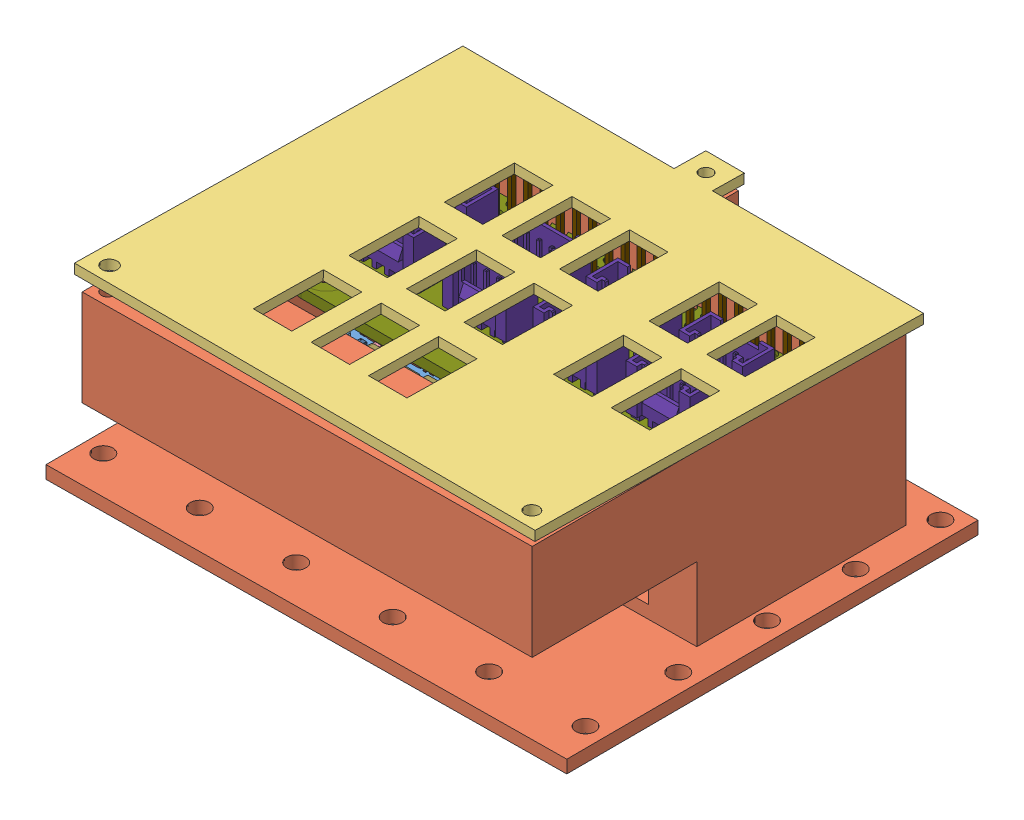
SolidWorks assembly RapberryPiZeroAndHat, configuration Default. Lengths in mm.
Overall size (81.55 32.34 66.18).
89 component instances, 21 part files, 142 mates.
Components (placement in the parent):
- Raspberry_pizero_PCB-1: Raspberry_pizero_PCB [Default] at (-51.2564 20.0966 13.0542) size (65 1 30)
- Micro USB_input_female (short)-SMT-1: Micro USB_input_female (short)-SMT [Default] at (-42.3564 22.3216 26.5042) size (7.98 2.94 5.43)
- Micro USB_input_female (short)-SMT-2: Micro USB_input_female (short)-SMT [Default] at (-29.7564 22.3216 26.5042) size (7.98 2.94 5.43)
- 0204 - Capacitor-1: 0204 - Capacitor [Default] at (-66.1059 21.3466 14.3973) size (1 0.5 0.6)
- 0204 - Capacitor-2: 0204 - Capacitor [Default] at (-66.1059 21.3466 13.6661) size (1 0.5 0.6)
- 0204 - Capacitor-3: 0204 - Capacitor [Default] at (-66.4957 21.3466 8.5689) size (1 0.5 0.6)
- 0204 - Capacitor-4: 0204 - Capacitor [Default] at (-66.4957 21.3466 9.5922) size (1 0.5 0.6)
- 0204 - Capacitor-5: 0204 - Capacitor [Default] at (-66.4957 21.3466 10.5547) size (1 0.5 0.6)
- 0204 - Capacitor-6: 0204 - Capacitor [Default] at (-66.4957 21.3466 11.4563) size (1 0.5 0.6)
- 0204 - Capacitor-7: 0204 - Capacitor [Default] at (-66.4957 21.3466 12.4125) size (1 0.5 0.6)
- 0204 - Capacitor-8: 0204 - Capacitor [Default] at (-54.2619 21.3466 22.342) size (1 0.5 0.6)
- 0204 - Capacitor-9: 0204 - Capacitor [Default] at (-54.2619 21.3466 24.3333) size (1 0.5 0.6)
- 0204 - Capacitor-10: 0204 - Capacitor [Default] at (-63.0188 21.3466 22.4185) x (0 0 1) z (-1 0 0) size (1 0.5 0.6)
- 0204 - Capacitor-11: 0204 - Capacitor [Default] at (-62.8505 21.3466 22.4185) x (0 0 -1) z (1 0 0) size (1 0.5 0.6)
- 0204 - Capacitor-12: 0204 - Capacitor [Default] at (-61.9536 21.3466 22.4185) x (0 0 -1) z (1 0 0) size (1 0.5 0.6)
- 0204 - Capacitor-13: 0204 - Capacitor [Default] at (-60.535 21.3466 22.4217) x (0 0 1) z (-1 0 0) size (1 0.5 0.6)
- 0204 - Capacitor-14: 0204 - Capacitor [Default] at (-60.2749 21.3466 22.4217) x (0 0 -1) z (1 0 0) size (1 0.5 0.6)
- 0204 - Capacitor-15: 0204 - Capacitor [Default] at (-59.4762 21.3466 22.4217) x (0 0 -1) z (1 0 0) size (1 0.5 0.6)
- 0204 - Capacitor-16: 0204 - Capacitor [Default] at (-58.5578 21.3466 22.4217) x (0 0 -1) z (1 0 0) size (1 0.5 0.6)
- 0204 - Capacitor-17: 0204 - Capacitor [Default] at (-57.7282 21.3466 22.4217) x (0 0 -1) z (1 0 0) size (1 0.5 0.6)
- 0204 - Capacitor-18: 0204 - Capacitor [Default] at (-49.7633 21.3466 17.2973) size (1 0.5 0.6)
- 0204 - Capacitor-19: 0204 - Capacitor [Default] at (-49.7656 21.3466 20.4911) size (1 0.5 0.6)
- 0204 - Capacitor-20: 0204 - Capacitor [Default] at (-49.7656 21.3466 19.5641) size (1 0.5 0.6)
- 0204 - Capacitor-21: 0204 - Capacitor [Default] at (-49.7656 21.3466 18.764) size (1 0.5 0.6)
- 0204 - Capacitor-22: 0204 - Capacitor [Default] at (-49.7656 21.3466 18.0575) size (1 0.5 0.6)
- 0204 - Capacitor-23: 0204 - Capacitor [Default] at (-50.3207 21.3466 16.1412) size (1 0.5 0.6)
- 0204 - Capacitor-24: 0204 - Capacitor [Default] at (-50.3207 21.3466 15.1225) size (1 0.5 0.6)
- 0204 - Capacitor-25: 0204 - Capacitor [Default] at (-50.3207 21.3466 14.0903) size (1 0.5 0.6)
- 0204 - Capacitor-26: 0204 - Capacitor [Default] at (-50.3207 21.3466 13.2438) size (1 0.5 0.6)
- 0204 - Capacitor-27: 0204 - Capacitor [Default] at (-44.527 21.3466 13.1418) size (1 0.5 0.6)
- 0204 - Capacitor-28: 0204 - Capacitor [Default] at (-44.527 21.3466 12.278) size (1 0.5 0.6)
- 0204 - Capacitor-29: 0204 - Capacitor [Default] at (-53.3159 21.3466 7.4799) size (1 0.5 0.6)
- 0204 - Capacitor-30: 0204 - Capacitor [Default] at (-59.3985 21.3466 7.1313) x (0 0 -1) z (1 0 0) size (1 0.5 0.6)
- 0204 - Capacitor-31: 0204 - Capacitor [Default] at (-57.9118 21.3466 7.1313) x (0 0 1) z (-1 0 0) size (1 0.5 0.6)
- 0204 - Capacitor-32: 0204 - Capacitor [Default] at (-63.5406 21.3466 7.1313) x (0 0 1) z (-1 0 0) size (1 0.5 0.6)
- 0204- Resistor-15: 0204- Resistor [Default] at (-44.5223 21.4522 15.4193) x (-1 0 0) z (0 -1 0) size (0.99 0.51 0.36)
- 0204- Resistor-14: 0204- Resistor [Default] at (-44.5223 21.4522 14.3417) x (-1 0 0) z (0 -1 0) size (0.99 0.51 0.36)
- 0204- Resistor-13: 0204- Resistor [Default] at (-44.5223 21.4522 12.4047) x (-1 0 0) z (0 -1 0) size (0.99 0.51 0.36)
- 0204- Resistor-4: 0204- Resistor [Default] at (-42.6936 21.4522 18.4076) x (-1 0 0) z (0 -1 0) size (0.99 0.51 0.36)
- 0204- Resistor-5: 0204- Resistor [Default] at (-39.831 21.4522 18.1462) x (0 0 1) z (0 -1 0) size (0.99 0.51 0.36)
- 0204- Resistor-7: 0204- Resistor [Default] at (-66.5004 21.4522 19.8533) x (-1 0 0) z (0 -1 0) size (0.99 0.51 0.36)
- 0204- Resistor-9: 0204- Resistor [Default] at (-79.148 21.4522 17.7279) x (-1 0 0) z (0 -1 0) size (0.99 0.51 0.36)
- 0204- Resistor-10: 0204- Resistor [Default] at (-60.3595 21.4522 7.1266) x (0 0 -1) z (0 -1 0) size (0.99 0.51 0.36)
- 0204- Resistor-11: 0204- Resistor [Default] at (-42.6893 21.4522 11.6167) x (-1 0 0) z (0 -1 0) size (0.99 0.51 0.36)
- 0204- Resistor-12: 0204- Resistor [Default] at (-21.8613 21.4522 20.9026) x (-1 0 0) z (0 -1 0) size (0.99 0.51 0.36)
- CAP-0306-1: CAP-0306 [Default] at (-50.0081 21.4966 8.9291) size (1.6 0.8 0.9)
- CAP-0306-2: CAP-0306 [Default] at (-82.3562 21.4966 19.4035) x (0 0 1) z (-1 0 0) size (1.6 0.8 0.9)
- Raspberry_pizero_BCM2835 with VC4-2: Raspberry_pizero_BCM2835 with VC4 [Default] at (-57.9267 21.5466 14.7194) x (1 0 0) z (0 0 -1) size (12 0.65 12)
- Crystal 3.4x2.4mm-1: Crystal 3.4x2.4mm [Default] at (-66.1441 21.0966 17.5946) x (0 0 1) z (-1 0 0) size (3.2 1 2.4)
- 0204- Resistor-16: 0204- Resistor [Default] at (-68.5745 21.4522 5.9384) x (0 0 1) z (0 -1 0) size (0.99 0.51 0.36)
- 0204- Resistor-17: 0204- Resistor [Default] at (-70.0781 21.4522 5.9384) x (0 0 1) z (0 -1 0) size (0.99 0.51 0.36)
- 0805- Capacitor-1: 0805- Capacitor [Default] at (-56.2106 21.9966 5.1919) x (1 0 0) z (0 -1 0) size (2 1.25 0.9)
- 0805- Capacitor-2: 0805- Capacitor [Default] at (-56.2106 21.9966 7.3589) x (1 0 0) z (0 -1 0) size (2 1.25 0.9)
- 0805- Capacitor-3: 0805- Capacitor [Default] at (-36.3007 21.9966 25.1368) x (1 0 0) z (0 -1 0) size (2 1.25 0.9)
- 0805- Capacitor-4: 0805- Capacitor [Default] at (-32.5762 21.9966 16.3326) x (0 0 1) z (0 -1 0) size (2 1.25 0.9)
- 0805- Capacitor-5: 0805- Capacitor [Default] at (-30.7451 21.9966 16.3326) x (0 0 -1) z (0 -1 0) size (2 1.25 0.9)
- 0805- Capacitor-6: 0805- Capacitor [Default] at (-26.001 21.9966 15.5523) x (0 0 -1) z (0 -1 0) size (2 1.25 0.9)
- 0805- Capacitor-7: 0805- Capacitor [Default] at (-24.0466 21.9966 15.5523) x (0 0 -1) z (0 -1 0) size (2 1.25 0.9)
- 0204 - Capacitor-33: 0204 - Capacitor [Default] at (-56.3601 21.3466 22.4168) x (0 0 1) z (-1 0 0) size (1 0.5 0.6)
- 0204 - Capacitor Brown-35: 0204 - Capacitor Brown [Default] at (-64.6013 21.3466 26.5277) size (1 0.5 0.6)
- 0204 - Capacitor Brown-36: 0204 - Capacitor Brown [Default] at (-50.3207 21.3466 12.214) size (1 0.5 0.6)
- 0204 - Capacitor Brown-37: 0204 - Capacitor Brown [Default] at (-50.3207 21.3466 11.0963) size (1 0.5 0.6)
- 0204 - Capacitor Brown-38: 0204 - Capacitor Brown [Default] at (-50.3207 21.3466 10.1084) size (1 0.5 0.6)
- 0204 - Capacitor Brown-39: 0204 - Capacitor Brown [Default] at (-44.527 21.3466 11.1151) size (1 0.5 0.6)
- 0204 - Capacitor Brown-40: 0204 - Capacitor Brown [Default] at (-42.694 21.3466 12.1364) size (1 0.5 0.6)
- 0204 - Capacitor Brown-41: 0204 - Capacitor Brown [Default] at (-80.9029 21.3466 20.8434) size (1 0.5 0.6)
- 0204- Resistor-21: 0204- Resistor [Default] at (-79.0538 21.4522 20.9432) x (1 0 0) z (0 -1 0) size (0.99 0.51 0.36)
- 6-Pin SOT-1: 6-Pin SOT [Default] at (-80.2098 21.0966 19.4296) x (0 0 1) z (0 1 0) size (1.5 1.84 0.95)
- micro sd molex-1: micro sd molex [Default] at (-74.7768 21.6766 -33.0961) x (0 0 1) z (0 1 0) size (11.95 11.4 1.45)
- hdmi type C-1: hdmi type C [Default] at (-71.3564 22.9466 28.6542) size (12.9 4.05 7.7)
- Voltage Regulator 3x3mm 12-Pin-1: Voltage Regulator 3x3mm 12-Pin [Default] at (-26.5859 21.0966 14.3315) x (1 0 0) z (0 1 0) size (3 4.1 1.2)
- 1210 inductor-1: 1210 inductor [Default] at (-50.6117 20.9774 6.5916) x (0 0 1) z (0 1 0) size (3.26 2.86 0.75)
- 0204 - Capacitor-34: 0204 - Capacitor [Default] at (-53.3159 21.3466 6.4804) size (1 0.5 0.6)
- raspberry_pi_B+_(bar_180_2x20)-1: raspberry_pi_B+_(bar_180_2x20) [Default] at (-75.3864 23.5966 0.2742) x (0 0 -1) z (-1 0 0) size (5.08 11.6 50.8)
- Grove Base Hat Zero-1: Grove Base Hat Zero [Défaut] at (-55.2748 26.5941 -51.9015) size (65 18.14 30)
  - Grove-Base-Hat-Zero-1: Grove-Base-Hat-Zero [Default] at (4.1184 5.5426 65) size (65 1.6 30)
  - Connecteur Grove (droit)-1: Connecteur Grove (droit) [Défaut] at (-20.1947 7.1426 64.26) size (10 11 5)
  - Connecteur Grove (droit)-2: Connecteur Grove (droit) [Défaut] at (-5.6902 7.1426 64.26) size (10 11 5)
  - Connecteur Grove (droit)-3: Connecteur Grove (droit) [Défaut] at (8.5295 7.1426 64.26) size (10 11 5)
  - Connecteur Grove (droit)-4: Connecteur Grove (droit) [Défaut] at (23.0725 7.1426 64.26) size (10 11 5)
  - Connecteur Grove (droit)-5: Connecteur Grove (droit) [Défaut] at (-20.1947 7.1426 72.5388) size (10 11 5)
  - Connecteur Grove (droit)-6: Connecteur Grove (droit) [Défaut] at (-5.6902 7.1426 72.5388) size (10 11 5)
  - Connecteur Grove (droit)-7: Connecteur Grove (droit) [Défaut] at (8.5295 7.1426 72.5388) size (10 11 5)
  - Connecteur Grove (droit)-8: Connecteur Grove (droit) [Défaut] at (23.0725 7.1426 72.5388) size (10 11 5)
  - HE10 Connecteur Male Femelle-1: HE10 Connecteur Male Femelle [Défaut] at (28.1484 4.769 52.5627) x (0 0 -1) z (-1 0 0) size (5.08 18.1 50.8)
    - HE10 Male 2x13-1: HE10 Male 2x13 [Default] at (0.2927 -0.2736 48.26) size (5.08 10.66 50.8)
    - HE10 Femelle 2x13-1: HE10 Femelle 2x13 [30] at (-3.4373 7.7664 49.53) x (0 0 1) z (0 1 0) size (50.76 5 8.5)
- boitier-1: boitier [Défaut] at (-86.7468 -2.1435 -41.1762) x (-0.007168 -0.003846 -0.999967) z (0.99997 0.003021 -0.007179) size (65.29 28.5 81)
- chapeau-1: chapeau [Défaut] at (-19.6116 47.3677 29.2244) x (0.999986 -0.004806 -0.002219) z (-0.004764 -0.999819 0.01841) size (72 66 1.5)
Mates (geometry in assembly coordinates):
- Coincident1: coincident anti-aligned: plane of Raspberry_pizero_PCB-1 through (-80.7564 21.0966 1.0542) normal (0 1 0); plane of Micro USB_input_female (short)-SMT-1 through (-46.4124 21.0966 24.8966) normal (0 -1 0)
- Coincident2: coincident anti-aligned: plane of Raspberry_pizero_PCB-1 through (-80.7564 21.0966 1.0542) normal (0 1 0); plane of Micro USB_input_female (short)-SMT-2 through (-33.8124 21.0966 24.8966) normal (0 -1 0)
- Coincident3: coincident aligned: plane of 0204 - Capacitor-13 through (-60.837 21.5916 22.4217) normal (0 1 0); plane of 0204 - Capacitor-14 through (-59.9729 21.5916 22.4217) normal (0 1 0)
- Coincident4: coincident aligned: plane of 0204 - Capacitor-14 through (-59.9729 21.5916 22.4217) normal (0 1 0); plane of 0204 - Capacitor-15 through (-59.1742 21.5916 22.4217) normal (0 1 0)
- Coincident5: coincident aligned: plane of 0204 - Capacitor-15 through (-59.1742 21.5916 22.4217) normal (0 1 0); plane of 0204 - Capacitor-16 through (-58.2558 21.5916 22.4217) normal (0 1 0)
- Coincident6: coincident aligned: plane of 0204 - Capacitor-16 through (-58.2558 21.5916 22.4217) normal (0 1 0); plane of 0204 - Capacitor-17 through (-57.4262 21.5916 22.4217) normal (0 1 0)
- Coincident7: coincident aligned: plane of 0204 - Capacitor-17 through (-57.4262 21.5916 22.4217) normal (0 1 0); plane of 0204 - Capacitor-18 through (-49.7633 21.5916 17.5993) normal (0 1 0)
- Coincident8: coincident aligned: plane of 0204 - Capacitor-18 through (-49.7633 21.5916 17.5993) normal (0 1 0); plane of 0204 - Capacitor-19 through (-49.7656 21.5916 20.7931) normal (0 1 0)
- Coincident9: coincident aligned: plane of 0204 - Capacitor-19 through (-49.7656 21.5916 20.7931) normal (0 1 0); plane of 0204 - Capacitor-20 through (-49.7656 21.5916 19.8661) normal (0 1 0)
- Coincident10: coincident aligned: plane of 0204 - Capacitor-20 through (-49.7656 21.5916 19.8661) normal (0 1 0); plane of 0204 - Capacitor-21 through (-49.7656 21.5916 19.066) normal (0 1 0)
- Coincident11: coincident aligned: plane of 0204 - Capacitor-21 through (-49.7656 21.5916 19.066) normal (0 1 0); plane of 0204 - Capacitor-22 through (-49.7656 21.5916 18.3595) normal (0 1 0)
- Coincident12: coincident aligned: plane of 0204 - Capacitor-22 through (-49.7656 21.5916 18.3595) normal (0 1 0); plane of 0204 - Capacitor-23 through (-50.3207 21.5916 16.4432) normal (0 1 0)
- Coincident13: coincident aligned: plane of 0204 - Capacitor-23 through (-50.3207 21.5916 16.4432) normal (0 1 0); plane of 0204 - Capacitor-24 through (-50.3207 21.5916 15.4245) normal (0 1 0)
- Coincident14: coincident aligned: plane of 0204 - Capacitor-24 through (-50.3207 21.5916 15.4245) normal (0 1 0); plane of 0204 - Capacitor-25 through (-50.3207 21.5916 14.3923) normal (0 1 0)
- Coincident15: coincident aligned: plane of 0204 - Capacitor-25 through (-50.3207 21.5916 14.3923) normal (0 1 0); plane of 0204 - Capacitor-26 through (-50.3207 21.5916 13.5458) normal (0 1 0)
- Coincident16: coincident aligned: plane of 0204 - Capacitor-26 through (-50.3207 21.5916 13.5458) normal (0 1 0); plane of 0204 - Capacitor-27 through (-44.527 21.5916 13.4438) normal (0 1 0)
- Coincident17: coincident aligned: plane of 0204 - Capacitor-27 through (-44.527 21.5916 13.4438) normal (0 1 0); plane of 0204 - Capacitor-28 through (-44.527 21.5916 12.58) normal (0 1 0)
- Coincident18: coincident aligned: plane of 0204 - Capacitor-28 through (-44.527 21.5916 12.58) normal (0 1 0); plane of 0204 - Capacitor-29 through (-53.3159 21.5916 7.7819) normal (0 1 0)
- Coincident19: coincident aligned: plane of 0204 - Capacitor-29 through (-53.3159 21.5916 7.7819) normal (0 1 0); plane of 0204 - Capacitor-31 through (-58.2138 21.5916 7.1313) normal (0 1 0)
- Coincident20: coincident aligned: plane of 0204 - Capacitor-30 through (-59.0965 21.5916 7.1313) normal (0 1 0); plane of 0204 - Capacitor-31 through (-58.2138 21.5916 7.1313) normal (0 1 0)
- Coincident21: coincident aligned: plane of 0204 - Capacitor-30 through (-59.0965 21.5916 7.1313) normal (0 1 0); plane of 0204 - Capacitor-32 through (-63.8426 21.5916 7.1313) normal (0 1 0)
- Coincident22: coincident aligned: plane of 0204 - Capacitor-1 through (-66.1059 21.5916 14.6993) normal (0 1 0); plane of 0204 - Capacitor-32 through (-63.8426 21.5916 7.1313) normal (0 1 0)
- Coincident23: coincident aligned: plane of 0204 - Capacitor-1 through (-66.1059 21.5916 14.6993) normal (0 1 0); plane of 0204 - Capacitor-2 through (-66.1059 21.5916 13.9681) normal (0 1 0)
- Coincident24: coincident aligned: plane of 0204 - Capacitor-2 through (-66.1059 21.5916 13.9681) normal (0 1 0); plane of 0204 - Capacitor-3 through (-66.4957 21.5916 8.8709) normal (0 1 0)
- Coincident25: coincident aligned: plane of 0204 - Capacitor-3 through (-66.4957 21.5916 8.8709) normal (0 1 0); plane of 0204 - Capacitor-4 through (-66.4957 21.5916 9.8942) normal (0 1 0)
- Coincident26: coincident aligned: plane of 0204 - Capacitor-4 through (-66.4957 21.5916 9.8942) normal (0 1 0); plane of 0204 - Capacitor-5 through (-66.4957 21.5916 10.8567) normal (0 1 0)
- Coincident27: coincident aligned: plane of 0204 - Capacitor-5 through (-66.4957 21.5916 10.8567) normal (0 1 0); plane of 0204 - Capacitor-6 through (-66.4957 21.5916 11.7583) normal (0 1 0)
- Coincident28: coincident aligned: plane of 0204 - Capacitor-6 through (-66.4957 21.5916 11.7583) normal (0 1 0); plane of 0204 - Capacitor-7 through (-66.4957 21.5916 12.7145) normal (0 1 0)
- Coincident29: coincident aligned: plane of 0204 - Capacitor-7 through (-66.4957 21.5916 12.7145) normal (0 1 0); plane of 0204 - Capacitor-8 through (-54.2619 21.5916 22.644) normal (0 1 0)
- Coincident31: coincident aligned: plane of 0204 - Capacitor-9 through (-54.2619 21.5916 24.6353) normal (0 1 0); plane of 0204 - Capacitor-10 through (-63.3208 21.5916 22.4185) normal (0 1 0)
- Coincident30: coincident aligned: plane of 0204 - Capacitor-8 through (-54.2619 21.5916 22.644) normal (0 1 0); plane of 0204 - Capacitor-9 through (-54.2619 21.5916 24.6353) normal (0 1 0)
- Coincident32: coincident aligned: plane of 0204 - Capacitor-10 through (-63.3208 21.5916 22.4185) normal (0 1 0); plane of 0204 - Capacitor-11 through (-62.5485 21.5916 22.4185) normal (0 1 0)
- Coincident33: coincident aligned: plane of 0204 - Capacitor-11 through (-62.5485 21.5916 22.4185) normal (0 1 0); plane of 0204 - Capacitor-12 through (-61.6516 21.5916 22.4185) normal (0 1 0)
- Coincident34: coincident anti-aligned: plane of Raspberry_pizero_PCB-1 through (-80.7564 21.0966 1.0542) normal (0 1 0); plane of 0204 - Capacitor-9 through (-54.6369 21.0966 24.6333) normal (0 -1 0)
- Coincident35: coincident aligned: plane of 0204 - Capacitor-25 through (-50.8207 21.0966 14.3903) normal (-1 0 0); plane of 0204 - Capacitor-26 through (-50.8207 21.0966 13.5438) normal (-1 0 0)
- Coincident36: coincident aligned: plane of 0204 - Capacitor-24 through (-50.8207 21.0966 15.4225) normal (-1 0 0); plane of 0204 - Capacitor-25 through (-50.8207 21.0966 14.3903) normal (-1 0 0)
- Coincident37: coincident aligned: plane of 0204 - Capacitor-23 through (-50.8207 21.0966 16.4412) normal (-1 0 0); plane of 0204 - Capacitor-24 through (-50.8207 21.0966 15.4225) normal (-1 0 0)
- Coincident38: coincident aligned: plane of 0204 - Capacitor-27 through (-45.027 21.0966 13.4418) normal (-1 0 0); plane of 0204 - Capacitor-28 through (-45.027 21.0966 12.578) normal (-1 0 0)
- Parallel1: parallel anti-aligned: plane of Raspberry_pizero_PCB-1 through (-80.7564 21.0966 -1.9458) normal (0 0 -1); plane of 0204 - Capacitor-30 through (-59.0985 21.0966 7.6313) normal (0 0 1)
- Coincident39: coincident aligned: plane of 0204 - Capacitor-30 through (-59.0985 21.0966 6.6313) normal (0 0 -1); plane of 0204 - Capacitor-31 through (-58.2118 21.0966 6.6313) normal (0 0 -1)
- Coincident40: coincident aligned: plane of 0204 - Capacitor-30 through (-59.0985 21.0966 6.6313) normal (0 0 -1); plane of 0204 - Capacitor-32 through (-63.8406 21.0966 6.6313) normal (0 0 -1)
- Coincident41: coincident aligned: plane of 0204 - Capacitor-1 through (-66.6059 21.0966 14.6973) normal (-1 0 0); plane of 0204 - Capacitor-2 through (-66.6059 21.0966 13.9661) normal (-1 0 0)
- Coincident42: coincident aligned: plane of 0204 - Capacitor-3 through (-66.9957 21.0966 8.8689) normal (-1 0 0); plane of 0204 - Capacitor-4 through (-66.9957 21.0966 9.8922) normal (-1 0 0)
- Coincident43: coincident aligned: plane of 0204 - Capacitor-4 through (-66.9957 21.0966 9.8922) normal (-1 0 0); plane of 0204 - Capacitor-5 through (-66.9957 21.0966 10.8547) normal (-1 0 0)
- Coincident44: coincident aligned: plane of 0204 - Capacitor-5 through (-66.9957 21.0966 10.8547) normal (-1 0 0); plane of 0204 - Capacitor-6 through (-66.9957 21.0966 11.7563) normal (-1 0 0)
- Coincident45: coincident aligned: plane of 0204 - Capacitor-6 through (-66.9957 21.0966 11.7563) normal (-1 0 0); plane of 0204 - Capacitor-7 through (-66.9957 21.0966 12.7125) normal (-1 0 0)
- Coincident46: coincident aligned: plane of 0204 - Capacitor-8 through (-54.7619 21.0966 22.642) normal (-1 0 0); plane of 0204 - Capacitor-9 through (-54.7619 21.0966 24.6333) normal (-1 0 0)
- Parallel2: parallel anti-aligned: plane of Raspberry_pizero_PCB-1 through (-80.7564 21.0966 28.0542) normal (0 0 1); plane of 0204 - Capacitor-10 through (-63.3188 21.0966 21.9185) normal (0 0 -1)
- Coincident48: coincident aligned: plane of 0204 - Capacitor-10 through (-63.3188 21.0966 22.9185) normal (0 0 1); plane of 0204 - Capacitor-11 through (-62.5505 21.0966 22.9185) normal (0 0 1)
- Coincident49: coincident aligned: plane of 0204 - Capacitor-11 through (-62.5505 21.0966 22.9185) normal (0 0 1); plane of 0204 - Capacitor-12 through (-61.6536 21.0966 22.9185) normal (0 0 1)
- Parallel3: parallel anti-aligned: plane of Raspberry_pizero_PCB-1 through (-80.7564 21.0966 28.0542) normal (0 0 1); plane of 0204 - Capacitor-13 through (-60.835 21.0966 21.9217) normal (0 0 -1)
- Coincident51: coincident aligned: plane of 0204 - Capacitor-13 through (-60.835 21.0966 22.9217) normal (0 0 1); plane of 0204 - Capacitor-14 through (-59.9749 21.0966 22.9217) normal (0 0 1)
- Coincident52: coincident aligned: plane of 0204 - Capacitor-14 through (-59.9749 21.0966 22.9217) normal (0 0 1); plane of 0204 - Capacitor-15 through (-59.1762 21.0966 22.9217) normal (0 0 1)
- Coincident53: coincident aligned: plane of 0204 - Capacitor-15 through (-59.1762 21.0966 22.9217) normal (0 0 1); plane of 0204 - Capacitor-16 through (-58.2578 21.0966 22.9217) normal (0 0 1)
- Coincident54: coincident aligned: plane of 0204 - Capacitor-16 through (-58.2578 21.0966 22.9217) normal (0 0 1); plane of 0204 - Capacitor-17 through (-57.4282 21.0966 22.9217) normal (0 0 1)
- Parallel7: parallel anti-aligned: plane of Raspberry_pizero_PCB-1 through (-80.7564 21.0966 28.0542) normal (0 0 1); plane of CAP-0306-2 through (-82.8062 21.0966 18.6035) normal (0 0 -1)
- Parallel8: parallel aligned: plane of Raspberry_pizero_PCB-1 through (-18.7564 21.0966 25.0542) normal (1 0 0); plane of CAP-0306-1 through (-49.2081 21.0966 9.3791) normal (1 0 0)
- Coincident77: coincident aligned: plane of 0204 - Capacitor-21 through (-50.2656 21.0966 19.064) normal (-1 0 0); plane of 0204 - Capacitor-22 through (-50.2656 21.0966 18.3575) normal (-1 0 0)
- Coincident78: coincident aligned: plane of 0204 - Capacitor-20 through (-50.2656 21.0966 19.8641) normal (-1 0 0); plane of 0204 - Capacitor-21 through (-50.2656 21.0966 19.064) normal (-1 0 0)
- Coincident79: coincident aligned: plane of 0204 - Capacitor-19 through (-50.2656 21.0966 20.7911) normal (-1 0 0); plane of 0204 - Capacitor-20 through (-50.2656 21.0966 19.8641) normal (-1 0 0)
- Coincident80: coincident aligned: plane of Micro USB_input_female (short)-SMT-1 through (-39.2364 21.3596 23.8542) normal (0 0 -1); plane of Micro USB_input_female (short)-SMT-2 through (-26.6364 21.3596 23.8542) normal (0 0 -1)
- Distance1: distance = 41.4 mm: point of Micro USB_input_female (short)-SMT-1; plane of Raspberry_pizero_PCB-1 through (-83.7564 21.0966 25.0542) normal (-1 0 0)
- Distance3: distance = 0.8 mm aligned: plane of Micro USB_input_female (short)-SMT-1 through (-46.2564 21.0476 28.8542) normal (0 0 1); plane of Raspberry_pizero_PCB-1 through (-80.7564 21.0966 28.0542) normal (0 0 1)
- Distance4: distance = 54 mm: unknown of Micro USB_input_female (short)-SMT-2; plane of Raspberry_pizero_PCB-1 through (-83.7564 21.0966 25.0542) normal (-1 0 0)
- Coincident86: coincident anti-aligned: plane of Raspberry_pizero_PCB-1 through (-80.7564 21.0966 1.0542) normal (0 1 0); plane of Raspberry_pizero_BCM2835 with VC4-2 through (-57.9267 21.0966 14.7194) normal (0 -1 0)
- Parallel10: parallel anti-aligned: plane of Raspberry_pizero_BCM2835 with VC4-2 through (-63.9267 21.0966 8.7194) normal (0 0 -1); plane of Raspberry_pizero_PCB-1 through (-80.7564 21.0966 28.0542) normal (0 0 1)
- Coincident88: coincident anti-aligned: plane of Raspberry_pizero_PCB-1 through (-80.7564 21.0966 1.0542) normal (0 1 0); plane of CAP-0306-1 through (-49.3831 21.0966 9.3791) normal (0 -1 0)
- Parallel11: parallel aligned: plane of Raspberry_pizero_PCB-1 through (-80.7564 21.0966 28.0542) normal (0 0 1); plane of 0204 - Capacitor-7 through (-66.4957 21.1016 13.0115) normal (0 0 1)
- Coincident94: coincident aligned: plane of 0204 - Capacitor-30 through (-59.0985 21.0966 6.6313) normal (0 0 -1); plane of 0204- Resistor-10 through (-60.1055 21.0966 6.6313) normal (0 0 -1)
- Coincident95: coincident anti-aligned: plane of Raspberry_pizero_PCB-1 through (-80.7564 21.0966 1.0542) normal (0 1 0); plane of 0204- Resistor-10 through (-60.1055 21.0966 6.8345) normal (0 -1 0)
- Coincident96: coincident aligned: plane of 0204- Resistor-14 through (-44.8144 21.0966 14.0877) normal (0 -1 0); plane of 0204- Resistor-13 through (-44.8144 21.0966 12.1507) normal (0 -1 0)
- Coincident97: coincident aligned: plane of 0204- Resistor-15 through (-44.8144 21.0966 15.1653) normal (0 -1 0); plane of 0204- Resistor-14 through (-44.8144 21.0966 14.0877) normal (0 -1 0)
- Coincident98: coincident aligned: plane of 0204- Resistor-15 through (-44.8144 21.0966 15.1653) normal (0 -1 0); plane of 0204- Resistor-4 through (-42.9857 21.0966 18.1536) normal (0 -1 0)
- Coincident99: coincident anti-aligned: plane of Raspberry_pizero_PCB-1 through (-80.7564 21.0966 1.0542) normal (0 1 0); plane of 0204- Resistor-15 through (-44.8144 21.0966 15.1653) normal (0 -1 0)
- Coincident101: coincident aligned: plane of 0204- Resistor-5 through (-40.085 21.0966 18.4383) normal (0 -1 0); plane of 0204- Resistor-11 through (-42.3972 21.0966 11.3627) normal (0 -1 0)
- Coincident102: coincident aligned: plane of 0204- Resistor-11 through (-42.3972 21.0966 11.3627) normal (0 -1 0); plane of 0204- Resistor-12 through (-21.5692 21.0966 20.6486) normal (0 -1 0)
- Coincident103: coincident anti-aligned: plane of Raspberry_pizero_PCB-1 through (-80.7564 21.0966 1.0542) normal (0 1 0); plane of Crystal 3.4x2.4mm-1 through (-66.1441 21.0966 17.5946) normal (0 -1 0)
- Parallel12: parallel aligned: plane of Crystal 3.4x2.4mm-1 through (-67.3441 21.7966 15.9946) normal (-1 0 0); plane of Raspberry_pizero_BCM2835 with VC4-2 through (-63.9267 21.0966 8.7194) normal (-1 0 0)
- Coincident104: coincident anti-aligned: plane of Raspberry_pizero_PCB-1 through (-80.7564 21.0966 1.0542) normal (0 1 0); plane of 0204- Resistor-9 through (-78.8559 21.0966 17.4739) normal (0 -1 0)
- Parallel13: parallel aligned: plane of Raspberry_pizero_PCB-1 through (-80.7564 21.0966 28.0542) normal (0 0 1); plane of 0204- Resistor-9 through (-78.2985 21.4532 17.9829) normal (0 0 1)
- Coincident105: coincident anti-aligned: plane of Raspberry_pizero_PCB-1 through (-80.7564 21.0966 1.0542) normal (0 1 0); plane of CAP-0306-2 through (-82.8062 21.0966 20.0285) normal (0 -1 0)
- Coincident106: coincident aligned: plane of 0204 - Capacitor-28 through (-44.027 21.0966 12.578) normal (1 0 0); plane of 0204- Resistor-13 through (-44.027 21.0966 12.1507) normal (1 0 0)
- Coincident107: coincident aligned: plane of 0204 - Capacitor-27 through (-44.027 21.0966 13.4418) normal (1 0 0); plane of 0204- Resistor-14 through (-44.027 21.0966 14.0877) normal (1 0 0)
- Parallel14: parallel aligned: plane of Raspberry_pizero_PCB-1 through (-80.7564 21.0966 28.0542) normal (0 0 1); plane of 0204- Resistor-14 through (-43.6728 21.4532 14.5967) normal (0 0 1)
- Coincident110: coincident aligned: plane of 0204- Resistor-15 through (-44.027 21.0966 15.1653) normal (1 0 0); plane of 0204- Resistor-14 through (-44.027 21.0966 14.0877) normal (1 0 0)
- Parallel15: parallel aligned: plane of 0204- Resistor-15 through (-44.027 21.0966 15.1653) normal (1 0 0); plane of 0204- Resistor-4 through (-42.1983 21.0966 18.1536) normal (1 0 0)
- Parallel16: parallel aligned: plane of Raspberry_pizero_PCB-1 through (-80.7564 21.0966 28.0542) normal (0 0 1); plane of 0204- Resistor-5 through (-40.085 21.0966 18.6415) normal (0 0 1)
- Coincident112: coincident anti-aligned: plane of Raspberry_pizero_PCB-1 through (-80.7564 21.0966 1.0542) normal (0 1 0); plane of 0204- Resistor-5 through (-40.085 21.0966 18.4383) normal (0 -1 0)
- Parallel17: parallel aligned: plane of Raspberry_pizero_PCB-1 through (-18.7564 21.0966 25.0542) normal (1 0 0); plane of 0204- Resistor-12 through (-21.366 21.0966 20.6486) normal (1 0 0)
- Parallel18: parallel aligned: plane of 0204- Resistor-11 through (-42.194 21.0966 11.3627) normal (1 0 0); plane of 0204- Resistor-12 through (-21.366 21.0966 20.6486) normal (1 0 0)
- Coincident115: coincident anti-aligned: plane of Raspberry_pizero_PCB-1 through (-80.7564 21.0966 1.0542) normal (0 1 0); plane of 0204- Resistor-16 through (-68.8285 21.0966 5.6463) normal (0 -1 0)
- Coincident116: coincident aligned: plane of 0204- Resistor-16 through (-68.8295 21.4532 5.0889) normal (0 1 0); plane of 0204- Resistor-17 through (-70.3331 21.4532 5.0889) normal (0 1 0)
- Coincident118: coincident aligned: plane of 0204- Resistor-16 through (-68.8285 21.0966 6.4337) normal (0 0 1); plane of 0204- Resistor-17 through (-70.3321 21.0966 6.4337) normal (0 0 1)
- Parallel19: parallel anti-aligned: plane of Raspberry_pizero_PCB-1 through (-80.7564 21.0966 -1.9458) normal (0 0 -1); plane of 0204- Resistor-17 through (-70.3321 21.0966 6.4337) normal (0 0 1)
- Coincident121: coincident anti-aligned: plane of Raspberry_pizero_PCB-1 through (-80.7564 21.0966 1.0542) normal (0 1 0); plane of 0805- Capacitor-1 through (-57.2106 21.0966 5.8169) normal (0 -1 0)
- Coincident122: coincident anti-aligned: plane of Raspberry_pizero_PCB-1 through (-80.7564 21.0966 1.0542) normal (0 1 0); plane of 0805- Capacitor-2 through (-57.2106 21.0966 7.9839) normal (0 -1 0)
- Coincident123: coincident anti-aligned: plane of Raspberry_pizero_PCB-1 through (-80.7564 21.0966 1.0542) normal (0 1 0); plane of 0805- Capacitor-3 through (-35.3007 21.0966 24.5118) normal (0 -1 0)
- Coincident124: coincident anti-aligned: plane of Raspberry_pizero_PCB-1 through (-80.7564 21.0966 1.0542) normal (0 1 0); plane of 0805- Capacitor-4 through (-33.2012 21.0966 15.3326) normal (0 -1 0)
- Coincident125: coincident anti-aligned: plane of Raspberry_pizero_PCB-1 through (-80.7564 21.0966 1.0542) normal (0 1 0); plane of 0805- Capacitor-5 through (-30.1201 21.0966 17.3326) normal (0 -1 0)
- Parallel21: parallel anti-aligned: plane of Raspberry_pizero_PCB-1 through (-80.7564 21.0966 28.0542) normal (0 0 1); plane of 0805- Capacitor-4 through (-32.5762 21.9966 15.3326) normal (0 0 -1)
- Coincident126: coincident aligned: plane of 0805- Capacitor-4 through (-32.5762 21.9966 17.3326) normal (0 0 1); plane of 0805- Capacitor-5 through (-30.7451 21.9966 17.3326) normal (0 0 1)
- Coincident127: coincident anti-aligned: plane of Raspberry_pizero_PCB-1 through (-80.7564 21.0966 1.0542) normal (0 1 0); plane of 0805- Capacitor-6 through (-25.376 21.0966 16.5523) normal (0 -1 0)
- Coincident128: coincident anti-aligned: plane of Raspberry_pizero_PCB-1 through (-80.7564 21.0966 1.0542) normal (0 1 0); plane of 0805- Capacitor-7 through (-23.4216 21.0966 16.5523) normal (0 -1 0)
- Coincident130: coincident aligned: plane of 0805- Capacitor-6 through (-26.001 21.9966 16.5523) normal (0 0 1); plane of 0805- Capacitor-7 through (-24.0466 21.9966 16.5523) normal (0 0 1)
- Parallel22: parallel aligned: plane of Raspberry_pizero_PCB-1 through (-80.7564 21.0966 28.0542) normal (0 0 1); plane of 0805- Capacitor-3 through (-37.3007 21.9966 25.7618) normal (0 0 1)
- Coincident131: coincident aligned: plane of 0805- Capacitor-1 through (-55.2106 21.9966 5.1919) normal (1 0 0); plane of 0805- Capacitor-2 through (-55.2106 21.9966 7.3589) normal (1 0 0)
- Parallel23: parallel anti-aligned: plane of Raspberry_pizero_PCB-1 through (-80.7564 21.0966 28.0542) normal (0 0 1); plane of 6-Pin SOT-1 through (-80.7098 22.0466 18.6796) normal (0 0 -1)
- Coincident134: coincident anti-aligned: plane of Raspberry_pizero_PCB-1 through (-80.7564 21.0966 1.0542) normal (0 1 0); plane of 6-Pin SOT-1 through (-80.9298 21.0966 20.0421) normal (0 -1 0)
- Coincident135: coincident anti-aligned: plane of Raspberry_pizero_PCB-1 through (-80.7564 21.0966 1.0542) normal (0 1 0); plane of micro sd molex-1 through (-71.1444 21.0966 16.7043) normal (0 -1 0)
- Parallel24: parallel aligned: plane of Raspberry_pizero_PCB-1 through (-80.7564 21.0966 -1.9458) normal (0 0 -1); plane of micro sd molex-1 through (-84.5393 22.448 5.3989) normal (0 0 -1)
- Coincident141: coincident anti-aligned: plane of Raspberry_pizero_PCB-1 through (-80.7564 21.0966 1.0542) normal (0 1 0); plane of hdmi type C-1 through (-77.8064 21.0966 20.9542) normal (0 -1 0)
- Distance5: distance = 12.4 mm: unknown of hdmi type C-1; plane of Raspberry_pizero_PCB-1 through (-83.7564 21.0966 25.0542) normal (-1 0 0)
- Distance6: distance = 17.2 mm: unknown of micro sd molex-1; plane of Raspberry_pizero_PCB-1 through (-80.7564 21.0966 28.0542) normal (0 0 1)
- Parallel25: parallel aligned: plane of Raspberry_pizero_PCB-1 through (-80.7564 21.0966 28.0542) normal (0 0 1); plane of hdmi type C-1 through (-71.3564 22.9466 28.6542) normal (0 0 1)
- Distance7: distance = 0.6 mm aligned: plane of hdmi type C-1 through (-71.3564 22.9466 28.6542) normal (0 0 1); plane of Raspberry_pizero_PCB-1 through (-80.7564 21.0966 28.0542) normal (0 0 1)
- Coincident144: coincident aligned: plane of 0204 - Capacitor-18 through (-49.7633 21.5916 17.5993) normal (0 1 0); plane of 0204 - Capacitor-33 through (-56.6621 21.5916 22.4168) normal (0 1 0)
- Parallel26: parallel anti-aligned: plane of Raspberry_pizero_PCB-1 through (-80.7564 21.0966 28.0542) normal (0 0 1); plane of 0204 - Capacitor-33 through (-56.6601 21.0966 21.9168) normal (0 0 -1)
- Coincident148: coincident anti-aligned: plane of Raspberry_pizero_PCB-1 through (-80.7564 21.0966 1.0542) normal (0 1 0); plane of 0204- Resistor-21 through (-79.3459 21.0966 21.1972) normal (0 -1 0)
- Coincident149: coincident anti-aligned: plane of Raspberry_pizero_PCB-1 through (-80.7564 21.0966 1.0542) normal (0 1 0); plane of 0204 - Capacitor Brown-41 through (-81.2779 21.0966 21.1434) normal (0 -1 0)
- Parallel27: parallel aligned: plane of Raspberry_pizero_PCB-1 through (-80.7564 21.0966 28.0542) normal (0 0 1); plane of 0204- Resistor-21 through (-79.0538 21.4522 21.1972) normal (0 0 1)
- Parallel28: parallel aligned: plane of Raspberry_pizero_PCB-1 through (-80.7564 21.0966 28.0542) normal (0 0 1); plane of 0204 - Capacitor Brown-41 through (-80.9029 21.1016 21.4424) normal (0 0 1)
- Coincident153: coincident aligned: plane of 0204 - Capacitor Brown-36 through (-50.3207 21.5916 12.516) normal (0 1 0); plane of 0204 - Capacitor Brown-39 through (-44.527 21.5916 11.4171) normal (0 1 0)
- Coincident154: coincident aligned: plane of 0204 - Capacitor Brown-36 through (-50.3207 21.5916 12.516) normal (0 1 0); plane of 0204 - Capacitor Brown-37 through (-50.3207 21.5916 11.3983) normal (0 1 0)
- Coincident155: coincident aligned: plane of 0204 - Capacitor Brown-37 through (-50.3207 21.5916 11.3983) normal (0 1 0); plane of 0204 - Capacitor Brown-38 through (-50.3207 21.5916 10.4104) normal (0 1 0)
- Coincident156: coincident aligned: plane of 0204 - Capacitor-26 through (-49.8207 21.0966 13.5438) normal (1 0 0); plane of 0204 - Capacitor Brown-36 through (-49.8207 21.0966 12.514) normal (1 0 0)
- Coincident157: coincident aligned: plane of 0204 - Capacitor Brown-36 through (-49.8207 21.0966 12.514) normal (1 0 0); plane of 0204 - Capacitor Brown-37 through (-49.8207 21.0966 11.3963) normal (1 0 0)
- Coincident158: coincident aligned: plane of 0204 - Capacitor Brown-37 through (-49.8207 21.0966 11.3963) normal (1 0 0); plane of 0204 - Capacitor Brown-38 through (-49.8207 21.0966 10.4084) normal (1 0 0)
- Coincident159: coincident aligned: plane of 0204 - Capacitor-28 through (-44.027 21.0966 12.578) normal (1 0 0); plane of 0204 - Capacitor Brown-39 through (-44.027 21.0966 11.4151) normal (1 0 0)
- Coincident160: coincident aligned: plane of 0204 - Capacitor Brown-39 through (-44.527 21.5916 11.4171) normal (0 1 0); plane of 0204 - Capacitor Brown-40 through (-42.694 21.5916 12.4384) normal (0 1 0)
- Coincident161: coincident aligned: plane of 0204- Resistor-11 through (-42.194 21.0966 11.3627) normal (1 0 0); plane of 0204 - Capacitor Brown-40 through (-42.194 21.0966 12.4364) normal (1 0 0)
- Coincident163: coincident anti-aligned: plane of Raspberry_pizero_PCB-1 through (-80.7564 21.0966 1.0542) normal (0 1 0); plane of Voltage Regulator 3x3mm 12-Pin-1 through (-27.0359 21.0966 13.0327) normal (0 -1 0)
- Parallel30: parallel aligned: plane of Raspberry_pizero_PCB-1 through (-18.7564 21.0966 25.0542) normal (1 0 0); plane of Voltage Regulator 3x3mm 12-Pin-1 through (-26.8859 22.2966 13.5815) normal (1 0 0)
- Coincident167: coincident aligned: plane of 0204 - Capacitor-29 through (-53.3159 21.5916 7.7819) normal (0 1 0); plane of 0204 - Capacitor-34 through (-53.3159 21.5916 6.7824) normal (0 1 0)
- Coincident168: coincident aligned: plane of 0204 - Capacitor-29 through (-53.8159 21.0966 7.7799) normal (-1 0 0); plane of 0204 - Capacitor-34 through (-53.8159 21.0966 6.7804) normal (-1 0 0)
- Parallel33: parallel aligned: plane of Raspberry_pizero_PCB-1 through (-18.7564 21.0966 25.0542) normal (1 0 0); plane of 1210 inductor-1 through (-49.3622 21.2524 6.5916) normal (1 0 0)
- Coïncidente1: coincident anti-aligned: plane of Raspberry_pizero_PCB-1 through (-80.7564 21.0966 1.0542) normal (0 1 0); plane of raspberry_pi_B+_(bar_180_2x20)-1 through (-75.3864 21.0966 2.5142) normal (0 -1 0)
- Parallèle1: parallel aligned: plane of Raspberry_pizero_PCB-1 through (-80.7564 21.0966 -1.9458) normal (0 0 -1); plane of raspberry_pi_B+_(bar_180_2x20)-1 through (-61.7164 21.0966 -0.9958) normal (0 0 -1)
- Distance8: distance = 7.1 mm aligned: plane of raspberry_pi_B+_(bar_180_2x20)-1 through (-76.6564 21.0966 1.8442) normal (-1 0 0); plane of Raspberry_pizero_PCB-1 through (-83.7564 21.0966 25.0542) normal (-1 0 0)
- Distance9: distance = 0.95 mm aligned: plane of Raspberry_pizero_PCB-1 through (-80.7564 21.0966 -1.9458) normal (0 0 -1); plane of raspberry_pi_B+_(bar_180_2x20)-1 through (-74.4164 21.0966 -0.9958) normal (0 0 -1)
- Coïncidente3: coincident anti-aligned: line of raspberry_pi_B+_(bar_180_2x20)-1 through (-76.6564 23.5966 1.2442) axis (0 0 -1); line of Grove Base Hat Zero-1/HE10 Connecteur Male Femelle-1/HE10 Femelle 2x13-1 through (-76.6564 23.5966 -0.9015) axis (0 0 1)
- Parallèle2: parallel aligned: line of Raspberry_pizero_PCB-1 through (-80.7564 21.0966 28.0542) axis (1 0 0); line of Grove Base Hat Zero-1/Grove-Base-Hat-Zero-1 through (-80.6564 32.1366 28.0985) axis (1 0 0)
- Parallèle5: parallel aligned: line of Raspberry_pizero_PCB-1 through (-21.7564 21.0966 -1.9458) axis (-1 0 0); line of Grove Base Hat Zero-1/Grove-Base-Hat-Zero-1 through (-21.6564 32.1366 -1.9015) axis (-1 0 0)
